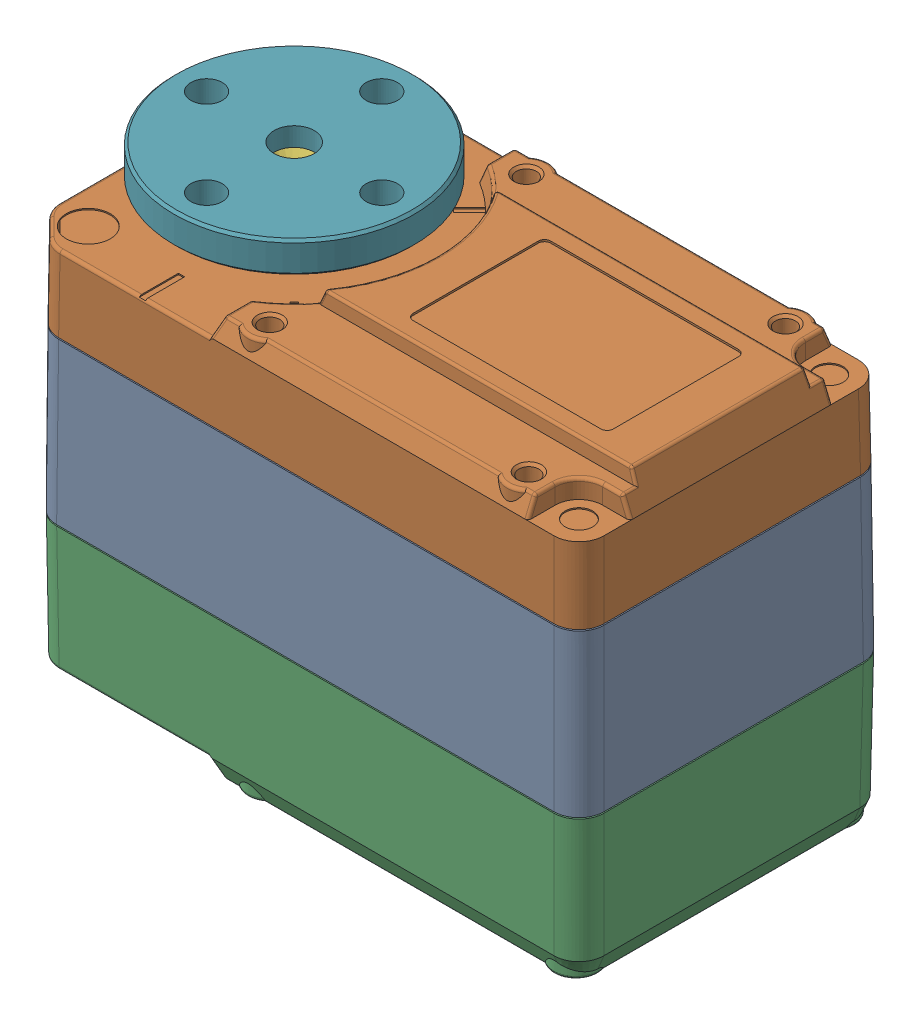
SolidWorks assembly ST3215_1, configuration Default. Lengths in mm.
Overall size (45.22 37.8 24.72).
7 component instances, 7 part files, 0 mates.
Components (placement in the parent):
- ZK_122-1: ZK_122 [Default] at (-27.959 1.6698 -21.9834) size (45.22 13.9 24.72)
- SG-ZIJI_15-1: SG-ZIJI_15 [Default] at (-27.959 1.6698 -21.9834) size (45 9.77 24.5)
- XG-ZIJI_16-1: XG-ZIJI_16 [Default] at (-27.959 1.6698 -21.9834) size (45.22 14.1 24.72)
- MOTOR-1723_3-1: MOTOR-1723_3 [Default] at (-27.959 -21.1802 -23.2334) x (0 0 -1) z (1 0 0) size (17.05 30.5 17.05)
- PCB-CHAZUO_92-1: PCB-CHAZUO_92 [Default] at (-27.959 1.6698 -21.9834) size (28.8 7.2 21.1)
- GE_27-1: GE_27 [Default] at (-53.459 -4.3302 -21.9834) x (1 0 0) z (0 -1 0) size (17.6 17.59 18.3)
- 金属舵盘（驱动）-1: 金属舵盘（驱动） [Default] at (-63.459 -15.7302 -21.9834) size (19.2 4.5 19.2)
